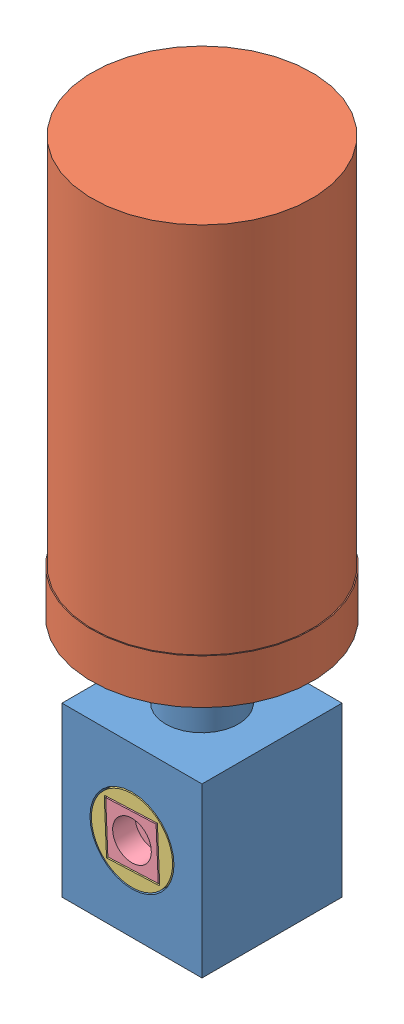
SolidWorks assembly EnsamblajePowderDispenser, configuration Predeterminado. Lengths in mm.
Overall size (81.88 245.5 81.88).
5 component instances, 5 part files, 10 mates.
Components (placement in the parent):
- CajaDelMedio-1: CajaDelMedio [Predeterminado] at (7.2227 -22.3574 60) size (50 91.5 50)
- Botella-1: Botella [Predeterminado] at (7.2227 23.1426 60) x (0.999311 0 0.037103) z (-0.037103 0 0.999311) size (79 190 79)
- CilindroCentral-1: CilindroCentral [Predeterminado] at (7.2227 7.6426 39) x (0 0 1) z (-0.043 0.999075 0) size (46 29 29)
- CuadradoTorque-1: CuadradoTorque [Predeterminado] at (7.2227 7.6426 75) x (-0.999075 -0.043 0) z (0 0 1) size (18 18 10)
- EjeSoporte-1: EjeSoporte [Predeterminado] at (7.2227 7.6426 33) x (1 0 0) z (0 -1 0) size (12 14 12)
Mates (geometry in assembly coordinates):
- Concéntrica1: concentric: cylinder of assembly; cylinder of assembly; cylinder of CajaDelMedio-1 through (7.2227 37.6426 60) axis (0 -1 0) radius 11; cylinder of Botella-1 through (7.2227 58.1426 60) axis (0 -1 0) radius 9.5
- Distancia1: distance = 14.5 mm: plane of assembly; plane of assembly; plane of CajaDelMedio-1 through (7.2227 37.6426 60) normal (0 1 0); plane of Botella-1 through (7.2227 23.1426 60) normal (0 -1 0)
- Concéntrica2: concentric: cylinder of assembly; cylinder of assembly; cylinder of CajaDelMedio-1 through (7.2227 7.6426 28) axis (0 0 1) radius 4; cylinder of CilindroCentral-1 through (7.2227 7.6426 47) axis (0 0 -1) radius 4
- Coincidente2: coincident: plane of assembly; plane of assembly; plane of CajaDelMedio-1 through (-17.7773 37.6426 85) normal (0 0 1); plane of CilindroCentral-1 through (7.2227 7.6426 85) normal (0 0 1)
- Concéntrica3: concentric: cylinder of assembly; cylinder of assembly; cylinder of CajaDelMedio-1 through (7.2227 7.6426 38) axis (0 0 1) radius 15; cylinder of CuadradoTorque-1 through (7.2227 7.6426 77) axis (0 0 1) radius 6.9
- Paralelo1: parallel: plane of assembly; plane of assembly; plane of CilindroCentral-1 through (-1.86 -2.2571 75) normal (-0.043 0.999075 0); plane of CuadradoTorque-1 through (16.6014 -0.9621 85) normal (0.043 -0.999075 0)
- Paralelo2: parallel: plane of assembly; plane of assembly; plane of CilindroCentral-1 through (-2.677 16.7253 75) normal (0.999075 0.043 0); plane of CuadradoTorque-1 through (-2.156 16.2473 85) normal (-0.999075 -0.043 0)
- Coincidente5: coincident: plane of assembly; plane of assembly; plane of CilindroCentral-1 through (7.2227 7.6426 75) normal (0 0 1); plane of CuadradoTorque-1 through (7.2227 7.6426 75) normal (0 0 -1)
- Coincidente6: coincident: plane of assembly; plane of assembly; plane of CajaDelMedio-1 through (-17.7773 37.6426 35) normal (0 0 -1); plane of EjeSoporte-1 through (7.2227 7.6426 35) normal (0 0 1)
- Concéntrica4: concentric: cylinder of assembly; cylinder of assembly; cylinder of CajaDelMedio-1 through (7.2227 7.6426 28) axis (0 0 1) radius 4; cylinder of EjeSoporte-1 through (7.2227 7.6426 47) axis (0 0 -1) radius 3.5
